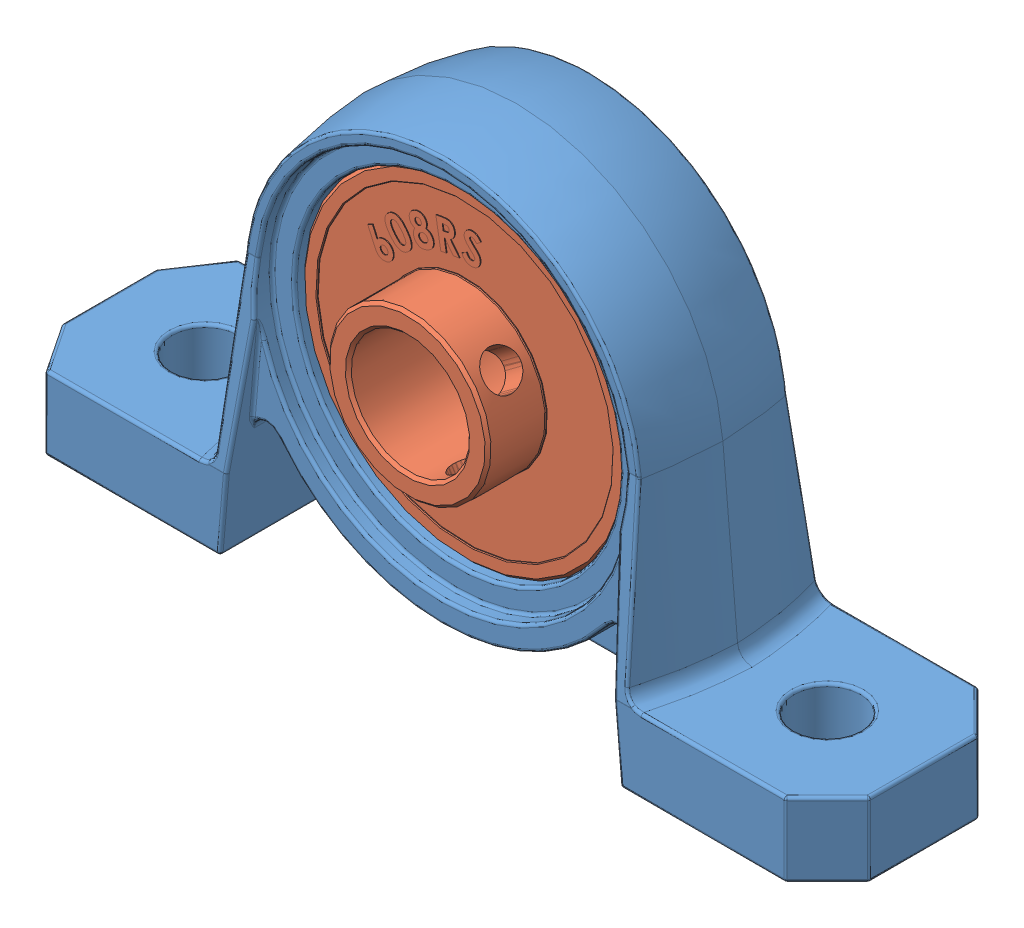
SolidWorks assembly KP08, configuration Default. Lengths in mm.
Overall size (55 40.88 13.92).
2 component instances, 2 part files, 4 mates.
Components (placement in the parent):
- KP08-2: KP08 [По умолчанию] at (2.2899 16 0) size (55 40.88 13.13)
- 608RS-2: 608RS [Default] at (2.2899 16 -3.5) x (0.16403 0.986455 0) z (0 0 1) size (22 22 10.85)
Mates (geometry in assembly coordinates):
- Концентричный2: concentric: cylinder of KP08-2 through (2.2899 16 5) axis (0 0 -1) radius 11; cylinder of 608RS-2 through (2.2899 16 3.5) axis (0 0 -1) radius 11
- Расстояние1: distance = 0.5 mm: plane of 608RS-2 through (2.2899 16 -3.5) normal (0 0 -1); plane of KP08-2 through (2.2899 16 -4) normal (0 0 -1)
- Совпадение2: coincident: circle of KP08-2; plane of assembly through (0 0 0) normal (0 0 1)
- Совпадение3: coincident: plane of KP08-2 through (2.2899 0 6.5) normal (0 -1 0); plane of assembly through (0 0 0) normal (0 1 0)
